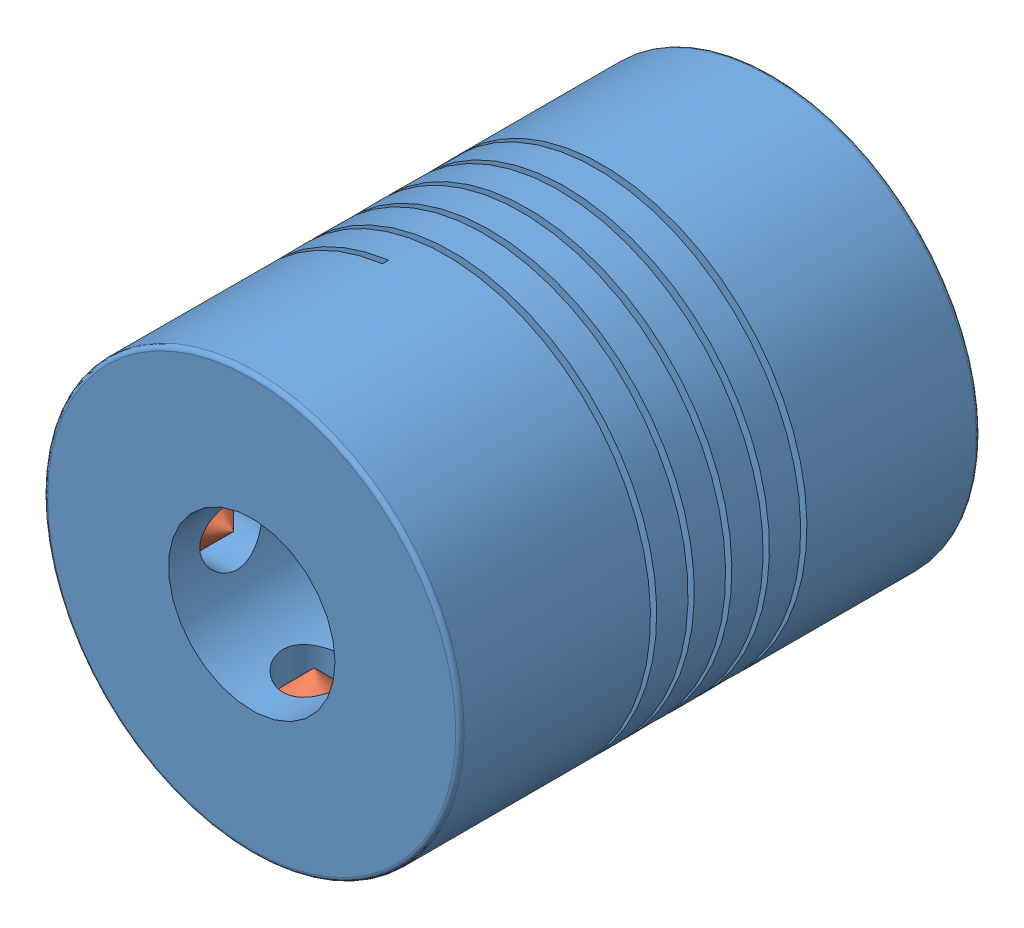
SolidWorks assembly Shaft Coupler 6.35mm 8mm, configuration Predeterminado. Lengths in mm.
Overall size (20.77 20.77 25).
5 component instances, 2 part files, 4 mates.
Components (placement in the parent):
- Shaft Coupler 6.35mm 8mm Body-1: Shaft Coupler 6.35mm 8mm Body [Predeterminado] at (-1.3837 -0.8648 0) size (20.77 20.77 25)
- socket set screw cone point_am-7: socket set screw cone point_am [B18.3.6M - M3 x 0.5 x 6 Hex Socket Cone Pt. SS --N] at (-11.2647 -0.8648 22) x (1 0 0) z (0 -0.164849 0.986319) size (6 3 3)
- socket set screw cone point_am-8: socket set screw cone point_am [B18.3.6M - M3 x 0.5 x 6 Hex Socket Cone Pt. SS --N] at (-11.1909 -0.8648 3) x (1 0 0) z (0 0.00677 0.999977) size (6 3 3)
- socket set screw cone point_am-9: socket set screw cone point_am [B18.3.6M - M3 x 0.5 x 6 Hex Socket Cone Pt. SS --N] at (-1.3837 -10.7654 3) x (0 1 0) z (-0.345086 0 0.938571) size (6 3 3)
- socket set screw cone point_am-10: socket set screw cone point_am [B18.3.6M - M3 x 0.5 x 6 Hex Socket Cone Pt. SS --N] at (-1.3837 -10.5992 22) x (0 1 0) z (-0.865685 0 0.500588) size (6 3 3)
Mates (geometry in assembly coordinates):
- Concéntrica7: concentric anti-aligned: cylinder of Shaft Coupler 6.35mm 8mm Body-1 through (-161.3837 -0.8648 22) axis (1 0 0) radius 1.5; cylinder of socket set screw cone point_am-7 through (-23.9647 -0.8648 22) axis (-1 0 0) radius 1.5
- Concéntrica8: concentric anti-aligned: cylinder of Shaft Coupler 6.35mm 8mm Body-1 through (-161.3837 -0.8648 3) axis (1 0 0) radius 1.5; cylinder of socket set screw cone point_am-8 through (-23.8909 -0.8648 3) axis (-1 0 0) radius 1.5
- Concéntrica10: concentric anti-aligned: cylinder of Shaft Coupler 6.35mm 8mm Body-1 through (-1.3837 -18.8648 3) axis (0 1 0) radius 1.5; cylinder of socket set screw cone point_am-9 through (-1.3837 -23.4654 3) axis (0 -1 0) radius 1.5
- Concéntrica11: concentric anti-aligned: cylinder of Shaft Coupler 6.35mm 8mm Body-1 through (-1.3837 -18.8648 22) axis (0 1 0) radius 1.5; cylinder of socket set screw cone point_am-10 through (-1.3837 -23.2992 22) axis (0 -1 0) radius 1.5
